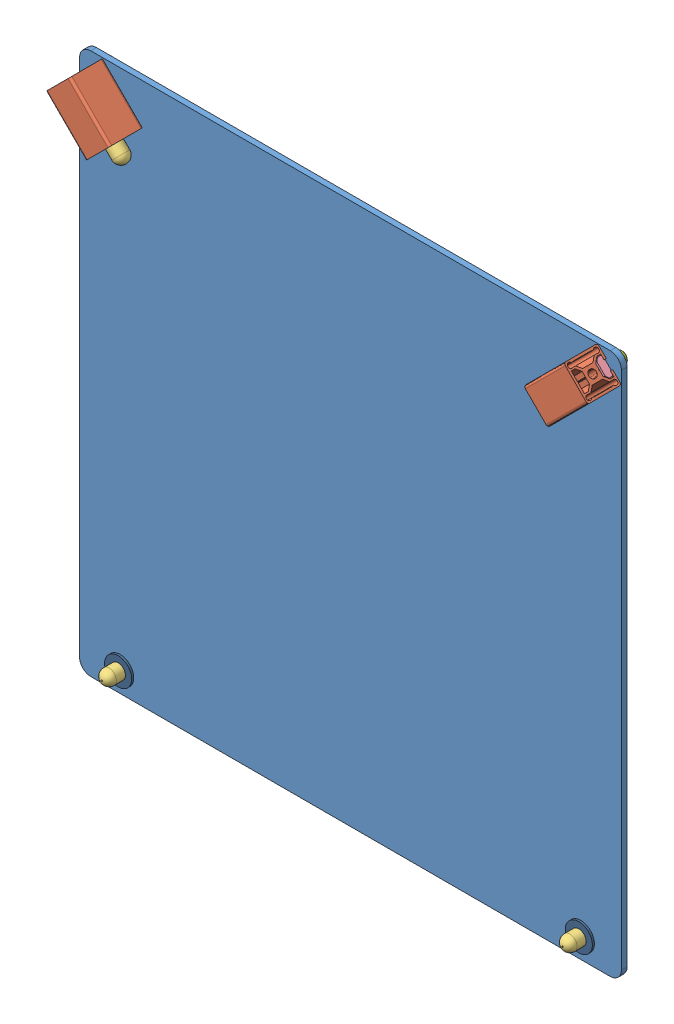
SolidWorks assembly Bed2-Assembly, configuration Default. Lengths in mm.
Overall size (480 480 46.46).
37 component instances, 10 part files, 83 mates.
Components (placement in the parent):
- Bed2_5mm-1: Bed2_5mm [Default] at origin size (480 480 5)
- HFS6_3030_50_LTP-1: HFS6_3030_50_LTP [Default] at (194.0381 194.0381 20) x (0.707107 -0.707107 0) z (-0.707107 -0.707107 0) size (30 30 50)
- HFS6_3030_50_LTP-2: HFS6_3030_50_LTP [Default] at (-194.0381 194.0381 20) x (0.707107 0.707107 0) z (0.707107 -0.707107 0) size (30 30 50)
- CJPQNBB8_13-1: CJPQNBB8_13 [Default] at (-194.0381 194.0381 20) x (0.707107 -0.707107 0) z (-0.707107 -0.707107 0) size (31.47 13 13)
- CJPQNBB8_13-2: CJPQNBB8_13 [Default] at (194.0381 194.0381 20) x (-0.707107 -0.707107 0) z (0.707107 -0.707107 0) size (31.47 13 13)
- HNTC6-1: HNTC6 [Default] at (-197.5736 197.5736 7) x (0.707107 0.707107 0) z (0 0 1) size (15 16 6.3)
- HNTC6-2: HNTC6 [Default] at (-213.9106 213.9106 7) x (-0.707107 -0.707107 0) z (0 0 1) size (15 16 6.3)
- HNTC6-3: HNTC6 [Default] at (-225.8579 225.8579 7) x (-0.707107 -0.707107 0) z (0 0 1) size (15 16 6.3)
- HNTC6-4: HNTC6 [Default] at (213.9106 213.9106 7) x (-0.707107 0.707107 0) z (0 0 1) size (15 16 6.3)
- HNTC6-5: HNTC6 [Default] at (197.5736 197.5736 7) x (0.707107 -0.707107 0) z (0 0 1) size (15 16 6.3)
- HNTC6-6: HNTC6 [Default] at (225.8579 225.8579 7) x (-0.707107 0.707107 0) z (0 0 1) size (15 16 6.3)
- 1-4_silicone_99604A115-1: 1-4_silicone_99604A115 [99604A115] at (-197.5736 197.5736 0) size (15.88 15.88 2.36)
- 1-4_silicone_99604A115-2: 1-4_silicone_99604A115 [99604A115] at (225.8579 225.8579 0) size (15.88 15.88 2.36)
- 1-4_silicone_99604A115-3: 1-4_silicone_99604A115 [99604A115] at (-225.8579 225.8579 0) size (15.88 15.88 2.36)
- 1-4_silicone_99604A115-4: 1-4_silicone_99604A115 [99604A115] at (197.5736 197.5736 0) size (15.88 15.88 2.36)
- 1-4_silicone_99604A115-5: 1-4_silicone_99604A115 [99604A115] at (213.9106 213.9106 0) size (15.88 15.88 2.36)
- 1-4_silicone_99604A115-6: 1-4_silicone_99604A115 [99604A115] at (-213.9106 213.9106 0) size (15.88 15.88 2.36)
- M6_ss_93475A250-1: M6_ss_93475A250 [93475A250] at (-197.5736 197.5736 -2.3622) size (12 12 1.4)
- M6_ss_93475A250-2: M6_ss_93475A250 [93475A250] at (213.9106 213.9106 -2.3622) size (12 12 1.4)
- M6_ss_93475A250-3: M6_ss_93475A250 [93475A250] at (-213.9106 213.9106 -2.3622) size (12 12 1.4)
- M6_ss_93475A250-4: M6_ss_93475A250 [93475A250] at (197.5736 197.5736 -2.3622) size (12 12 1.4)
- M6_ss_93475A250-5: M6_ss_93475A250 [93475A250] at (-225.8579 225.8579 -2.3622) size (12 12 1.4)
- M6_ss_93475A250-6: M6_ss_93475A250 [93475A250] at (225.8579 225.8579 -2.3622) size (12 12 1.4)
- M6x18_91292A136-1: M6x18_91292A136 [91292A136] at (-197.5736 197.5736 14.2378) size (10 10 24.53)
- M6x18_91292A136-2: M6x18_91292A136 [91292A136] at (-213.9106 213.9106 14.2378) size (10 10 24.53)
- M6x18_91292A136-3: M6x18_91292A136 [91292A136] at (-225.8579 225.8579 14.2378) size (10 10 24.53)
- M6x18_91292A136-4: M6x18_91292A136 [91292A136] at (197.5736 197.5736 14.2378) size (10 10 24.53)
- M6x18_91292A136-5: M6x18_91292A136 [91292A136] at (213.9106 213.9106 14.2378) size (10 10 24.53)
- M6x18_91292A136-6: M6x18_91292A136 [91292A136] at (225.8579 225.8579 14.2378) size (10 10 24.53)
- CJPQNBB8_13-3: CJPQNBB8_13 [Default] at (-204 -222 6.8) x (0 0 1) z (-0.99919 0.040233 0) size (31.47 13 13)
- CJPQNBB8_13-4: CJPQNBB8_13 [Default] at (204 -222 6.8) x (0 0 1) z (-0.9546 0.297892 0) size (31.47 13 13)
- 5-16_silicone_99604A119-1: 5-16_silicone_99604A119 [99604A119] at (-204 -222 0) size (17.46 17.46 2.36)
- 5-16_silicone_99604A119-2: 5-16_silicone_99604A119 [99604A119] at (204 -222 0) size (17.46 17.46 2.36)
- Nyloc_M8_flange_ss_92461A300-1: Nyloc_M8_flange_ss_92461A300 [92461A300] at (204 -222 -2.3622) x (1 0 0) z (0 1 0) size (14.2 9.28 14.2)
- Nyloc_M8_flange_ss_92461A300-2: Nyloc_M8_flange_ss_92461A300 [92461A300] at (-204 -222 -2.3622) x (1 0 0) z (0 1 0) size (14.2 9.28 14.2)
- M8_fender_ss_91116A160-1: M8_fender_ss_91116A160 [91116A160] at (204 -222 6.8) size (24 24 1.8)
- M8_fender_ss_91116A160-2: M8_fender_ss_91116A160 [91116A160] at (-204 -222 6.8) size (24 24 1.8)
Mates (geometry in assembly coordinates):
- Coincident1: coincident aligned: plane of Bed2_5mm-1 through (0 0 0) normal (0 0 1); plane of assembly through (0 0 0) normal (0 0 1)
- Coincident2: coincident aligned: plane of Bed2_5mm-1 through (0 0 0) normal (0 1 0); plane of assembly through (0 0 0) normal (0 1 0)
- Coincident3: coincident aligned: plane of Bed2_5mm-1 through (0 0 0) normal (1 0 0); plane of assembly through (0 0 0) normal (1 0 0)
- Concentric1: concentric anti-aligned: cylinder of HFS6_3030_50_LTP-2 through (-229.3934 229.3934 20) axis (0.707107 -0.707107 0) radius 3.4; cylinder of CJPQNBB8_13-1 through (-194.0381 194.0381 20) axis (-0.707107 0.707107 0) radius 4
- Concentric2: concentric anti-aligned: cylinder of HFS6_3030_50_LTP-1 through (229.3934 229.3934 20) axis (-0.707107 -0.707107 0) radius 3.4; cylinder of CJPQNBB8_13-2 through (194.0381 194.0381 20) axis (0.707107 0.707107 0) radius 4
- Coincident4: coincident anti-aligned: plane of HFS6_3030_50_LTP-1 through (184.8457 203.2304 33) normal (-0.707107 -0.707107 0); plane of CJPQNBB8_13-2 through (194.0381 194.0381 20) normal (0.707107 0.707107 0)
- Coincident5: coincident anti-aligned: plane of HFS6_3030_50_LTP-2 through (-203.2304 184.8457 33) normal (0.707107 -0.707107 0); plane of CJPQNBB8_13-1 through (-194.0381 194.0381 20) normal (-0.707107 0.707107 0)
- Coincident6: coincident anti-aligned: plane of Bed2_5mm-1 through (-240 -240 5) normal (0 0 1); plane of HFS6_3030_50_LTP-2 through (-238.5858 220.201 5) normal (0 0 -1)
- Coincident7: coincident anti-aligned: plane of Bed2_5mm-1 through (-240 -240 5) normal (0 0 1); plane of HFS6_3030_50_LTP-1 through (220.201 238.5858 5) normal (0 0 -1)
- Coincident8: coincident aligned: plane of HNTC6-1 through (-196.7958 191.2803 6.2) normal (0 0 -1); plane of HNTC6-2 through (-214.6884 220.2038 6.2) normal (0 0 -1)
- Coincident9: coincident aligned: plane of HNTC6-1 through (-196.7958 191.2803 6.2) normal (0 0 -1); plane of HNTC6-3 through (-226.6357 232.1511 6.2) normal (0 0 -1)
- Coincident10: coincident aligned: plane of HNTC6-4 through (220.2038 214.6884 6.2) normal (0 0 -1); plane of HNTC6-5 through (191.2803 196.7958 6.2) normal (0 0 -1)
- Coincident11: coincident aligned: plane of HNTC6-4 through (220.2038 214.6884 6.2) normal (0 0 -1); plane of HNTC6-6 through (232.1511 226.6357 6.2) normal (0 0 -1)
- Coincident12: coincident anti-aligned: plane of HNTC6-1; plane of HNTC6-2
- Coincident13: coincident anti-aligned: plane of HNTC6-1; plane of HNTC6-3
- Coincident14: coincident anti-aligned: plane of HNTC6-4; plane of HNTC6-5
- Coincident15: coincident aligned: plane of HNTC6-4; plane of HNTC6-6
- Coincident16: coincident anti-aligned: plane of CJPQNBB8_13-1 through (-194.0381 194.0381 20) normal (-0.707107 -0.707107 0); plane of HNTC6-1
- Coincident17: coincident anti-aligned: plane of HFS6_3030_50_LTP-2 through (-223.5598 235.227 7) normal (0 0 1); plane of HNTC6-1 through (-191.2803 196.7958 7) normal (0 0 -1)
- Coincident18: coincident anti-aligned: plane of CJPQNBB8_13-2 through (194.0381 194.0381 20) normal (0.707107 -0.707107 0); plane of HNTC6-4
- Coincident19: coincident anti-aligned: plane of HFS6_3030_50_LTP-1 through (235.227 223.5598 7) normal (0 0 1); plane of HNTC6-4 through (214.6884 220.2038 7) normal (0 0 -1)
- Coincident20: coincident aligned: plane of HFS6_3030_50_LTP-1 through (184.8457 203.2304 33) normal (-0.707107 -0.707107 0); plane of HNTC6-5 through (196.7958 191.2803 7) normal (-0.707107 -0.707107 0)
- Coincident21: coincident aligned: plane of HFS6_3030_50_LTP-2 through (-203.2304 184.8457 33) normal (0.707107 -0.707107 0); plane of HNTC6-1 through (-191.2803 196.7958 7) normal (0.707107 -0.707107 0)
- Concentric3: concentric aligned: cylinder of Bed2_5mm-1 through (-197.5736 197.5736 5) axis (0 0 -1) radius 3.25; cylinder of HNTC6-1 through (-197.5736 197.5736 12.5) axis (0 0 -1) radius 3
- Concentric4: concentric aligned: cylinder of Bed2_5mm-1 through (197.5736 197.5736 5) axis (0 0 -1) radius 3.25; cylinder of HNTC6-5 through (197.5736 197.5736 12.5) axis (0 0 -1) radius 3
- Concentric5: concentric aligned: cylinder of Bed2_5mm-1 through (-213.9106 213.9106 5) axis (0 0 -1) radius 3.25; cylinder of HNTC6-2 through (-213.9106 213.9106 12.5) axis (0 0 -1) radius 3
- Concentric6: concentric aligned: cylinder of Bed2_5mm-1 through (-225.8579 225.8579 5) axis (0 0 -1) radius 3.25; cylinder of HNTC6-3 through (-225.8579 225.8579 12.5) axis (0 0 -1) radius 3
- Concentric7: concentric aligned: cylinder of Bed2_5mm-1 through (213.9106 213.9106 5) axis (0 0 -1) radius 3.25; cylinder of HNTC6-4 through (213.9106 213.9106 12.5) axis (0 0 -1) radius 3
- Concentric8: concentric aligned: cylinder of Bed2_5mm-1 through (225.8579 225.8579 5) axis (0 0 -1) radius 3.25; cylinder of HNTC6-6 through (225.8579 225.8579 12.5) axis (0 0 -1) radius 3
- Coincident23: coincident aligned: plane of 1-4_silicone_99604A115-1 through (-197.5736 197.5736 -2.3622) normal (0 0 -1); plane of 1-4_silicone_99604A115-6 through (-213.9106 213.9106 -2.3622) normal (0 0 -1)
- Coincident24: coincident aligned: plane of 1-4_silicone_99604A115-1 through (-197.5736 197.5736 -2.3622) normal (0 0 -1); plane of 1-4_silicone_99604A115-5 through (213.9106 213.9106 -2.3622) normal (0 0 -1)
- Coincident25: coincident aligned: plane of 1-4_silicone_99604A115-1 through (-197.5736 197.5736 -2.3622) normal (0 0 -1); plane of 1-4_silicone_99604A115-4 through (197.5736 197.5736 -2.3622) normal (0 0 -1)
- Coincident26: coincident aligned: plane of 1-4_silicone_99604A115-1 through (-197.5736 197.5736 -2.3622) normal (0 0 -1); plane of 1-4_silicone_99604A115-3 through (-225.8579 225.8579 -2.3622) normal (0 0 -1)
- Coincident27: coincident aligned: plane of 1-4_silicone_99604A115-1 through (-197.5736 197.5736 -2.3622) normal (0 0 -1); plane of 1-4_silicone_99604A115-2 through (225.8579 225.8579 -2.3622) normal (0 0 -1)
- Coincident28: coincident aligned: plane of M6_ss_93475A250-1 through (-197.5736 197.5736 -3.7622) normal (0 0 -1); plane of M6_ss_93475A250-3 through (-213.9106 213.9106 -3.7622) normal (0 0 -1)
- Coincident29: coincident aligned: plane of M6_ss_93475A250-1 through (-197.5736 197.5736 -3.7622) normal (0 0 -1); plane of M6_ss_93475A250-2 through (213.9106 213.9106 -3.7622) normal (0 0 -1)
- Coincident30: coincident aligned: plane of M6_ss_93475A250-1 through (-197.5736 197.5736 -3.7622) normal (0 0 -1); plane of M6_ss_93475A250-6 through (225.8579 225.8579 -3.7622) normal (0 0 -1)
- Coincident31: coincident aligned: plane of M6_ss_93475A250-1 through (-197.5736 197.5736 -3.7622) normal (0 0 -1); plane of M6_ss_93475A250-5 through (-225.8579 225.8579 -3.7622) normal (0 0 -1)
- Coincident32: coincident aligned: plane of M6_ss_93475A250-1 through (-197.5736 197.5736 -3.7622) normal (0 0 -1); plane of M6_ss_93475A250-4 through (197.5736 197.5736 -3.7622) normal (0 0 -1)
- Concentric9: concentric aligned: cylinder of 1-4_silicone_99604A115-1 through (-197.5736 197.5736 -2.3622) axis (0 0 1) radius 7.9375; cylinder of M6_ss_93475A250-1 through (-197.5736 197.5736 -3.7622) axis (0 0 1) radius 6
- Coincident33: coincident anti-aligned: plane of 1-4_silicone_99604A115-1 through (-197.5736 197.5736 -2.3622) normal (0 0 -1); plane of M6_ss_93475A250-1 through (-197.5736 197.5736 -2.3622) normal (0 0 1)
- Concentric10: concentric aligned: cylinder of 1-4_silicone_99604A115-6 through (-213.9106 213.9106 -2.3622) axis (0 0 1) radius 7.9375; cylinder of M6_ss_93475A250-3 through (-213.9106 213.9106 -3.7622) axis (0 0 1) radius 6
- Concentric11: concentric aligned: cylinder of 1-4_silicone_99604A115-5 through (213.9106 213.9106 -2.3622) axis (0 0 1) radius 7.9375; cylinder of M6_ss_93475A250-2 through (213.9106 213.9106 -3.7622) axis (0 0 1) radius 6
- Concentric12: concentric aligned: cylinder of 1-4_silicone_99604A115-2 through (225.8579 225.8579 -2.3622) axis (0 0 1) radius 7.9375; cylinder of M6_ss_93475A250-6 through (225.8579 225.8579 -3.7622) axis (0 0 1) radius 6
- Concentric13: concentric aligned: cylinder of 1-4_silicone_99604A115-3 through (-225.8579 225.8579 -2.3622) axis (0 0 1) radius 7.9375; cylinder of M6_ss_93475A250-5 through (-225.8579 225.8579 -3.7622) axis (0 0 1) radius 6
- Concentric14: concentric aligned: cylinder of 1-4_silicone_99604A115-4 through (197.5736 197.5736 -2.3622) axis (0 0 1) radius 7.9375; cylinder of M6_ss_93475A250-4 through (197.5736 197.5736 -3.7622) axis (0 0 1) radius 6
- Coincident34: coincident anti-aligned: plane of Bed2_5mm-1 through (-240 -240 0) normal (0 0 -1); plane of 1-4_silicone_99604A115-1 through (-197.5736 197.5736 0) normal (0 0 1)
- Concentric15: concentric anti-aligned: cylinder of Bed2_5mm-1 through (-197.5736 197.5736 5) axis (0 0 -1) radius 3.25; cylinder of 1-4_silicone_99604A115-1 through (-197.5736 197.5736 -2.3622) axis (0 0 1) radius 7.9375
- Concentric16: concentric anti-aligned: cylinder of Bed2_5mm-1 through (-213.9106 213.9106 5) axis (0 0 -1) radius 3.25; cylinder of 1-4_silicone_99604A115-6 through (-213.9106 213.9106 -2.3622) axis (0 0 1) radius 7.9375
- Concentric17: concentric anti-aligned: cylinder of Bed2_5mm-1 through (-225.8579 225.8579 5) axis (0 0 -1) radius 3.25; cylinder of 1-4_silicone_99604A115-3 through (-225.8579 225.8579 -2.3622) axis (0 0 1) radius 7.9375
- Concentric18: concentric anti-aligned: cylinder of Bed2_5mm-1 through (225.8579 225.8579 5) axis (0 0 -1) radius 3.25; cylinder of 1-4_silicone_99604A115-2 through (225.8579 225.8579 -2.3622) axis (0 0 1) radius 7.9375
- Concentric19: concentric anti-aligned: cylinder of Bed2_5mm-1 through (213.9106 213.9106 5) axis (0 0 -1) radius 3.25; cylinder of 1-4_silicone_99604A115-5 through (213.9106 213.9106 -2.3622) axis (0 0 1) radius 7.9375
- Concentric20: concentric anti-aligned: cylinder of Bed2_5mm-1 through (197.5736 197.5736 5) axis (0 0 -1) radius 3.25; cylinder of 1-4_silicone_99604A115-4 through (197.5736 197.5736 -2.3622) axis (0 0 1) radius 7.9375
- Coincident35: coincident aligned: plane of M6x18_91292A136-1 through (-197.5736 197.5736 -3.7622) normal (0 0 1); plane of M6x18_91292A136-2 through (-213.9106 213.9106 -3.7622) normal (0 0 1)
- Coincident36: coincident aligned: plane of M6x18_91292A136-1 through (-197.5736 197.5736 -3.7622) normal (0 0 1); plane of M6x18_91292A136-3 through (-225.8579 225.8579 -3.7622) normal (0 0 1)
- Coincident37: coincident aligned: plane of M6x18_91292A136-1 through (-197.5736 197.5736 -3.7622) normal (0 0 1); plane of M6x18_91292A136-4 through (197.5736 197.5736 -3.7622) normal (0 0 1)
- Coincident38: coincident aligned: plane of M6x18_91292A136-1 through (-197.5736 197.5736 -3.7622) normal (0 0 1); plane of M6x18_91292A136-5 through (213.9106 213.9106 -3.7622) normal (0 0 1)
- Coincident39: coincident aligned: plane of M6x18_91292A136-1 through (-197.5736 197.5736 -3.7622) normal (0 0 1); plane of M6x18_91292A136-6 through (225.8579 225.8579 -3.7622) normal (0 0 1)
- Concentric21: concentric aligned: cylinder of M6_ss_93475A250-1 through (-197.5736 197.5736 -3.7622) axis (0 0 1) radius 6; cylinder of M6x18_91292A136-1 through (-197.5736 197.5736 -9.7622) axis (0 0 1) radius 5
- Coincident40: coincident anti-aligned: plane of M6_ss_93475A250-1 through (-197.5736 197.5736 -3.7622) normal (0 0 -1); plane of M6x18_91292A136-1 through (-197.5736 197.5736 -3.7622) normal (0 0 1)
- Concentric22: concentric aligned: cylinder of 1-4_silicone_99604A115-6 through (-213.9106 213.9106 -2.3622) axis (0 0 1) radius 7.9375; cylinder of M6x18_91292A136-2 through (-213.9106 213.9106 -9.7622) axis (0 0 1) radius 5
- Concentric23: concentric aligned: cylinder of 1-4_silicone_99604A115-3 through (-225.8579 225.8579 -2.3622) axis (0 0 1) radius 7.9375; cylinder of M6x18_91292A136-3 through (-225.8579 225.8579 -9.7622) axis (0 0 1) radius 5
- Concentric24: concentric aligned: cylinder of 1-4_silicone_99604A115-4 through (197.5736 197.5736 -2.3622) axis (0 0 1) radius 7.9375; cylinder of M6x18_91292A136-4 through (197.5736 197.5736 -9.7622) axis (0 0 1) radius 5
- Concentric25: concentric aligned: cylinder of 1-4_silicone_99604A115-5 through (213.9106 213.9106 -2.3622) axis (0 0 1) radius 7.9375; cylinder of M6x18_91292A136-5 through (213.9106 213.9106 -9.7622) axis (0 0 1) radius 5
- Concentric26: concentric aligned: cylinder of 1-4_silicone_99604A115-2 through (225.8579 225.8579 -2.3622) axis (0 0 1) radius 7.9375; cylinder of M6x18_91292A136-6 through (225.8579 225.8579 -9.7622) axis (0 0 1) radius 5
- Coincident43: coincident aligned: plane of 5-16_silicone_99604A119-1 through (-204 -222 -2.3622) normal (0 0 -1); plane of 5-16_silicone_99604A119-2 through (204 -222 -2.3622) normal (0 0 -1)
- Coincident44: coincident aligned: plane of M8_fender_ss_91116A160-1 through (204 -222 5) normal (0 0 -1); plane of M8_fender_ss_91116A160-2 through (-204 -222 5) normal (0 0 -1)
- Coincident45: coincident aligned: plane of Nyloc_M8_flange_ss_92461A300-1 through (209 -224.8868 -2.3622) normal (0 0 1); plane of Nyloc_M8_flange_ss_92461A300-2 through (-199 -224.8868 -2.3622) normal (0 0 1)
- Coincident46: coincident anti-aligned: plane of 5-16_silicone_99604A119-1 through (-204 -222 -2.3622) normal (0 0 -1); plane of Nyloc_M8_flange_ss_92461A300-2 through (-199 -224.8868 -2.3622) normal (0 0 1)
- Concentric27: concentric anti-aligned: cylinder of 5-16_silicone_99604A119-1 through (-204 -222 -2.3622) axis (0 0 1) radius 8.7312; cylinder of Nyloc_M8_flange_ss_92461A300-2 through (-204 -222 -2.3622) axis (0 0 -1) radius 7.1
- Concentric28: concentric anti-aligned: cylinder of 5-16_silicone_99604A119-2 through (204 -222 -2.3622) axis (0 0 1) radius 8.7312; cylinder of Nyloc_M8_flange_ss_92461A300-1 through (204 -222 -2.3622) axis (0 0 -1) radius 7.1
- Coincident47: coincident anti-aligned: plane of Bed2_5mm-1 through (-240 -240 0) normal (0 0 -1); plane of 5-16_silicone_99604A119-1 through (-204 -222 0) normal (0 0 1)
- Concentric29: concentric anti-aligned: cylinder of CJPQNBB8_13-3 through (-204 -222 56.8) axis (0 0 -1) radius 6.5; cylinder of 5-16_silicone_99604A119-1 through (-204 -222 -2.3622) axis (0 0 1) radius 8.7312
- Concentric30: concentric anti-aligned: cylinder of CJPQNBB8_13-4 through (204 -222 56.8) axis (0 0 -1) radius 6.5; cylinder of 5-16_silicone_99604A119-2 through (204 -222 -2.3622) axis (0 0 1) radius 8.7312
- Concentric31: concentric anti-aligned: cylinder of CJPQNBB8_13-3 through (-204 -222 56.8) axis (0 0 -1) radius 6.5; cylinder of M8_fender_ss_91116A160-2 through (-204 -222 5) axis (0 0 1) radius 12
- Coincident48: coincident anti-aligned: plane of CJPQNBB8_13-3 through (-204 -222 6.8) normal (0 0 -1); plane of M8_fender_ss_91116A160-2 through (-204 -222 6.8) normal (0 0 1)
- Coincident49: coincident anti-aligned: plane of Bed2_5mm-1 through (-240 -240 5) normal (0 0 1); plane of M8_fender_ss_91116A160-2 through (-204 -222 5) normal (0 0 -1)
- Concentric32: concentric anti-aligned: cylinder of CJPQNBB8_13-4 through (204 -222 56.8) axis (0 0 -1) radius 6.5; cylinder of M8_fender_ss_91116A160-1 through (204 -222 5) axis (0 0 1) radius 12
- Coincident50: coincident anti-aligned: plane of CJPQNBB8_13-4 through (204 -222 6.8) normal (0 0 -1); plane of M8_fender_ss_91116A160-1 through (204 -222 6.8) normal (0 0 1)
- Concentric33: concentric aligned: cylinder of Bed2_5mm-1 through (-204 -222 5) axis (0 0 -1) radius 4.4; cylinder of CJPQNBB8_13-3 through (-204 -222 56.8) axis (0 0 -1) radius 6.5
- Concentric34: concentric aligned: cylinder of Bed2_5mm-1 through (204 -222 5) axis (0 0 -1) radius 4.4; cylinder of CJPQNBB8_13-4 through (204 -222 56.8) axis (0 0 -1) radius 6.5
- PLANE2: unknown: unknown of HFS6_3030_50_LTP-1
- PLANE3: unknown: plane of assembly through (0 0 0) normal (0.707107 -0.707107 0); unknown of HFS6_3030_50_LTP-1
